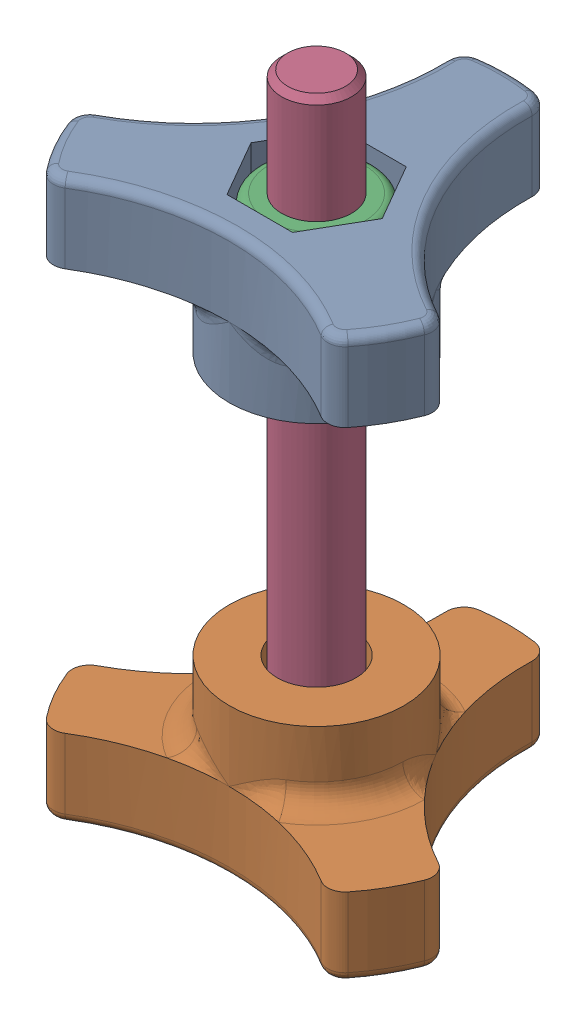
SolidWorks assembly TR23-RC-0700_30mm, configuration Default. Lengths in mm.
Overall size (41.18 75.3 36.41).
4 component instances, 4 part files, 0 mates.
Components (placement in the parent):
- TR23-RC-0050-1: TR23-RC-0050 [Default] at origin size (41.18 17 36.41)
- TR23-RC-0051-1: TR23-RC-0051 [Default] at (0 -30 0) x (-1 0 0) z (0 0 1) size (41.18 17 36.41)
- ISO 10511 M8 Locking Nut-1: ISO 10511 M8 Locking Nut [Default] at (0 9 0) x (0 0 -1) z (1 0 0) size (13 6.76 15.01)
- ISO 4017 - M8 x 70-N_ISO 4017 - M8 x 70-N-1: ISO 4017 - M8 x 70-N_ISO 4017 - M8 x 70-N [Default] at (0 -47.3 0) x (0 1 0) z (0 0 1) size (75.3 15.01 13)
